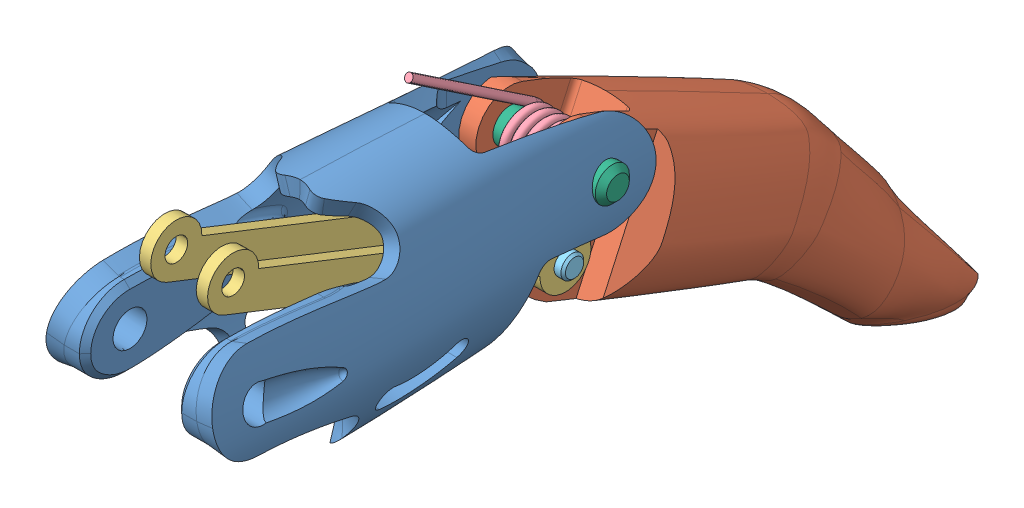
SolidWorks assembly 02-003, configuration 默认. Lengths in mm.
Overall size (17.27 39.83 78.45).
7 component instances, 6 part files, 12 mates.
Components (placement in the parent):
- 01-017-1: 01-017 [默认] at (13.3105 22.7476 50.5397) size (17.27 19.24 40.8)
- 01-018-1: 01-018 [默认] at (13.3105 22.5267 20.0851) x (1 0 0) z (0 0.413484 0.910511) size (12.29 17.46 47.7)
- 01-019-1: 01-019 [默认] at (15.3105 17.5628 15.2005) x (-1 0 0) z (0 -0.36621 -0.930532) size (1 6 36.5)
- 01-019-2: 01-019 [默认] at (10.3105 17.5628 15.2005) x (-1 0 0) z (0 -0.36621 -0.930532) size (1 6 36.5)
- 01-009-1: 01-009 [默认] at (11.7255 24.9701 14.5824) x (1 0 0) z (0 -0.840918 0.541163) size (5.44 18.26 4.7)
- 01-036-1: 01-036 [默认] at (18.3105 17.5628 15.2005) x (0 -0.45846 -0.888715) z (1 0 0) size (2 2 7.6)
- 01-035-1: 01-035 [默认] at (6.3105 24.9701 14.5824) x (0 -0.984187 0.177132) z (-1 0 0) size (3 3 14)
Mates (geometry in assembly coordinates):
- Concentric1: concentric aligned: cylinder of 01-017-1 through (21.9486 24.9701 14.5824) axis (-1 0 0) radius 1.5; cylinder of 01-035-1 through (6.3105 24.9701 14.5824) axis (-1 0 0) radius 1.5
- Width1: width aligned: plane of 01-035-1 through (20.3105 24.9701 14.5824) normal (1 0 0); plane of 01-035-1 through (6.3105 24.9701 14.5824) normal (-1 0 0); plane of 01-018-1 through (17.3105 13.9004 24.0026) normal (1 0 0); plane of 01-018-1 through (9.3105 13.9004 24.0026) normal (-1 0 0)
- Width2: width anti-aligned: plane of 01-017-1 through (9.3105 22.704 18.168) normal (1 0 0); plane of 01-017-1 through (17.3105 22.704 18.168) normal (-1 0 0); plane of 01-018-1 through (9.3105 13.9004 24.0026) normal (-1 0 0); plane of 01-018-1 through (17.3105 13.9004 24.0026) normal (1 0 0)
- Concentric2: concentric aligned: cylinder of 01-019-2 through (11.3105 17.5628 15.2005) axis (-1 0 0) radius 1; cylinder of 01-036-1 through (8.3105 17.5628 15.2005) axis (-1 0 0) radius 1
- Coincident1: coincident anti-aligned: plane of 01-018-1 through (11.3105 21.99 16.4849) normal (-1 0 0); plane of 01-019-2 through (11.3105 17.5628 15.2005) normal (1 0 0)
- Coincident2: coincident anti-aligned: plane of 01-018-1 through (15.3105 21.99 16.4849) normal (1 0 0); plane of 01-019-1 through (15.3105 17.5628 15.2005) normal (-1 0 0)
- Concentric5: concentric aligned: cylinder of 01-019-1 through (16.3105 30.6773 44.4282) axis (-1 0 0) radius 1; cylinder of 01-019-2 through (11.3105 30.6773 44.4282) axis (-1 0 0) radius 1
- Concentric6: concentric anti-aligned: cylinder of 01-018-1 through (13.3055 24.9701 14.5824) axis (1 0 0) radius 1.5; cylinder of 01-035-1 through (6.3105 24.9701 14.5824) axis (-1 0 0) radius 1.5
- Lock1: lock: unknown of 01-017-1; unknown of 01-009-1
- Concentric7: concentric anti-aligned: cylinder of 01-018-1 through (11.3105 17.5628 15.2005) axis (1 0 0) radius 1; cylinder of 01-036-1 through (8.3105 17.5628 15.2005) axis (-1 0 0) radius 1
- Width3: width aligned: plane of 01-036-1 through (9.5105 17.196 14.4896) normal (-1 0 0); plane of 01-036-1 through (17.1105 17.196 14.4896) normal (1 0 0); plane of 01-019-2 through (10.3105 17.5628 15.2005) normal (-1 0 0); plane of 01-019-1 through (16.3105 17.5628 15.2005) normal (1 0 0)
- Concentric8: concentric aligned: cylinder of 01-019-1 through (16.3105 17.5628 15.2005) axis (-1 0 0) radius 2.25; cylinder of 01-036-1 through (8.3105 17.5628 15.2005) axis (-1 0 0) radius 1
